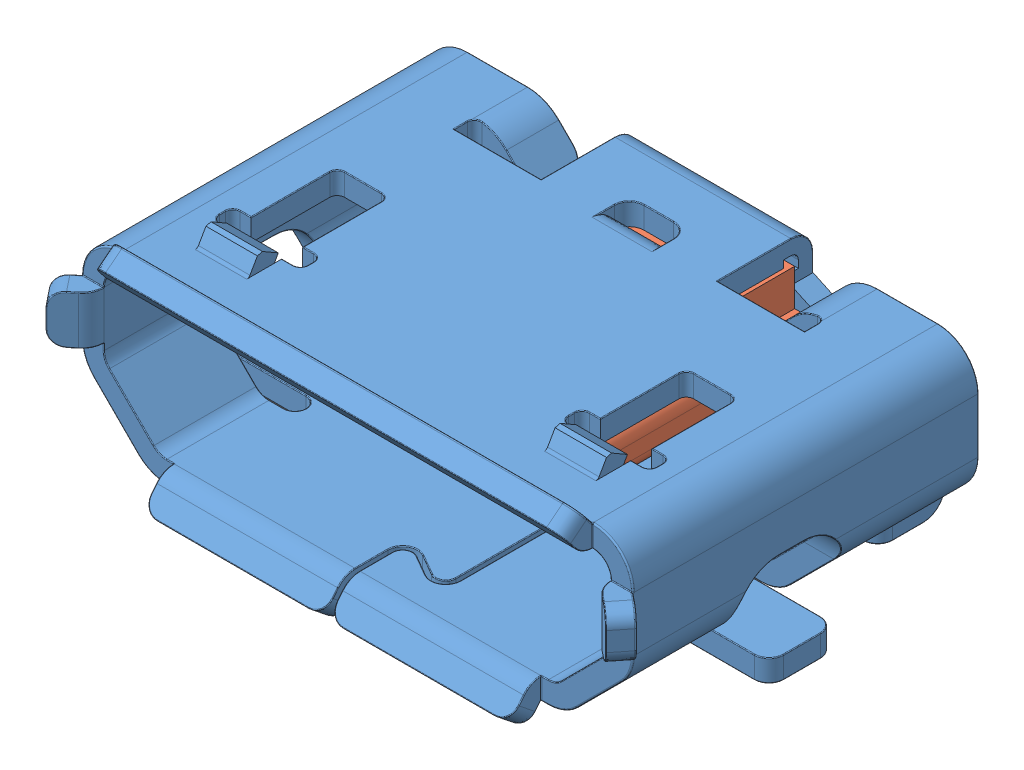
SolidWorks assembly Micro-USB-Buchse, configuration Default. Lengths in mm.
Overall size (7.97 2.92 5.43).
2 component instances, 2 part files, 3 mates.
Components (placement in the parent):
- Micro-USB-Outer-1: Micro-USB-Outer [Default] at (-14.4796 6.4719 -16.0085) size (7.97 2.92 5.43)
- Micro-USB-Inner-1: Micro-USB-Inner [Default] at (-14.4796 6.4719 -20.7085) size (6.9 2.16 4.2)
Mates (geometry in assembly coordinates):
- Coincident1: coincident anti-aligned: plane of Micro-USB-Outer-1 through (-17.6796 7.3969 -20.7085) normal (0 -1 0); plane of Micro-USB-Inner-1 through (-11.0296 7.3969 -19.5085) normal (0 1 0)
- Coincident2: coincident anti-aligned: plane of Micro-USB-Outer-1 through (-17.9296 6.4004 -20.7085) normal (1 0 0); plane of Micro-USB-Inner-1 through (-17.9296 7.3969 -19.5085) normal (-1 0 0)
- Coincident3: coincident anti-aligned: plane of Micro-USB-Outer-1 through (-13.2796 6.7737 -20.7085) normal (0 0 1); plane of Micro-USB-Inner-1 through (-17.9296 5.5469 -20.7085) normal (0 0 -1)
